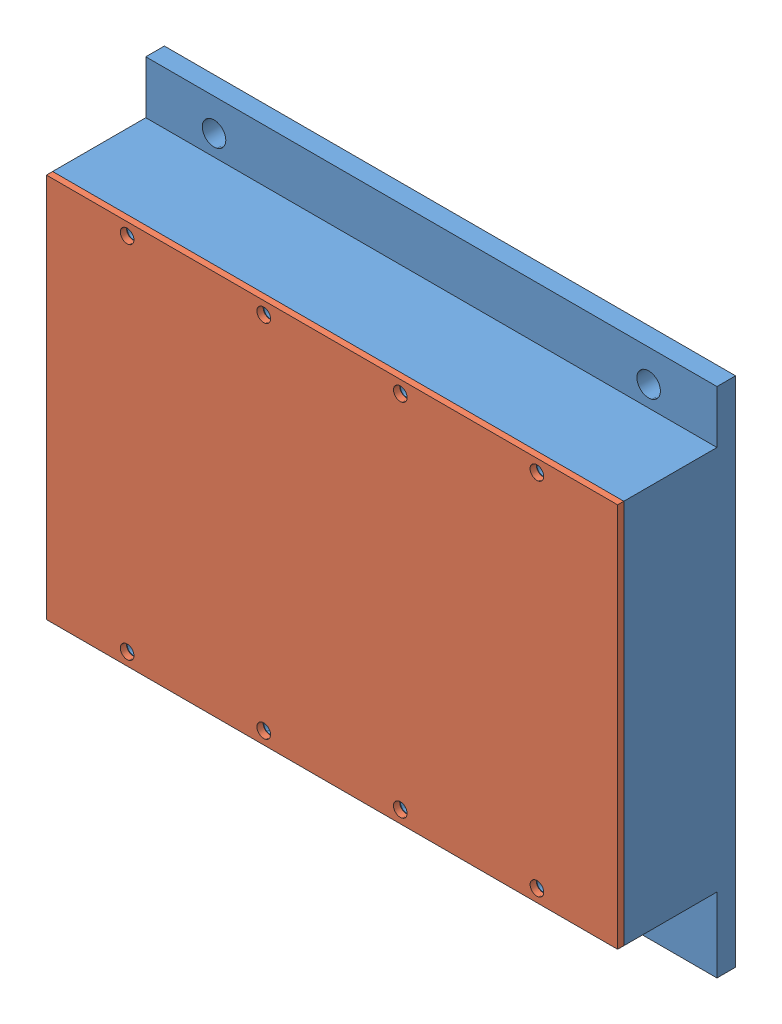
SolidWorks assembly B3_batterybox, configuration Default. Lengths in mm.
Overall size (92 82.5 20.29).
14 component instances, 6 part files, 40 mates.
Components (placement in the parent):
- B3_battery_case-1: B3_battery_case [Default] at (-27.6193 12.9444 0.2286) size (92 82.5 18)
- B3_battery_cover-1: B3_battery_cover [Default] at (-73.6193 43.9444 18.2286) size (92 62 1)
- B3_battery_insulator1-1: B3_battery_insulator1 [Default] at (-29.6748 38.9444 -2.4068) x (1 0 0) z (0 1 0) size (88.4 17 1)
- B3_battery_insulator1-2: B3_battery_insulator1 [Default] at (-25.5639 -14.0556 19.864) x (-1 0 0) z (0 1 0) size (88.4 17 1)
- B3_battery_insulator2-1: B3_battery_insulator2 [Default] at (15.5807 9.9046 1.8438) x (0 -1 0) z (0 0 1) size (52 1 17)
- B3_battery_insulator2-3: B3_battery_insulator2 [Default] at (-71.8193 9.9046 1.8438) x (0 -1 0) z (0 0 1) size (52 1 17)
- B3_battery_insulator3-1: B3_battery_insulator3 [Default] at (-40.702 30.9956 0.2286) x (1 0 0) z (0 -1 0) size (86.4 1 52)
- battery-8: battery [Default] at (-63.3443 -13.0556 8.4036) x (-0.702082 0 -0.712097) z (0.712097 0 -0.702082) size (14.35 52 14.35)
- battery-9: battery [Default] at (-48.9943 -13.0556 8.4036) x (-0.963236 0 -0.268658) z (0.268658 0 -0.963236) size (14.35 52 14.35)
- battery-10: battery [Default] at (-34.6443 -13.0556 8.4036) x (-0.96243 0 -0.271529) z (0.271529 0 -0.96243) size (14.35 52 14.35)
- battery-11: battery [Default] at (-20.2943 -13.0556 8.4036) x (0.998572 0 0.05343) z (-0.05343 0 0.998572) size (14.35 52 14.35)
- battery-12: battery [Default] at (-5.9443 -13.0556 8.4036) x (-0.654063 0 0.75644) z (-0.75644 0 -0.654063) size (14.35 52 14.35)
- battery-14: battery [Default] at (8.4057 -13.0556 8.4036) x (0.87582 0 0.482638) z (-0.482638 0 0.87582) size (14.35 52 14.35)
- B3_battery_insulator3-2: B3_battery_insulator3 [Default] at (-40.702 30.9956 15.5786) x (1 0 0) z (0 -1 0) size (86.4 1 52) (hidden)
Mates (geometry in assembly coordinates):
- Coincident13: coincident aligned: plane of B3_battery_insulator1-1 through (-71.8193 39.9444 17.2286) normal (0 0 1); plane of B3_battery_insulator1-2 through (16.5807 -13.0556 17.2286) normal (0 0 1)
- Coincident26: coincident anti-aligned: plane of B3_battery_insulator1-1 through (-29.6748 38.9444 -2.4068) normal (0 -1 0); plane of B3_battery_insulator2-1 through (16.5807 38.9444 0.2286) normal (0 1 0)
- Coincident29: coincident anti-aligned: plane of B3_battery_insulator1-1 through (-29.6748 38.9444 -2.4068) normal (0 -1 0); plane of B3_battery_insulator2-3 through (-70.8193 38.9444 0.2286) normal (0 1 0)
- Tangent30: tangent anti-aligned: plane of B3_battery_insulator2-1 through (15.5807 9.9046 1.8438) normal (-1 0 0); cylinder of battery-14 through (8.4057 37.9444 8.4036) axis (0 -1 0) radius 7.175
- Coincident46: coincident anti-aligned: plane of B3_battery_insulator1-2 through (-25.5639 -13.0556 19.864) normal (0 1 0); plane of battery-14 through (8.4057 -13.0556 8.4036) normal (0 -1 0)
- Coincident47: coincident anti-aligned: plane of B3_battery_insulator1-2 through (-25.5639 -13.0556 19.864) normal (0 1 0); plane of battery-12 through (-5.9443 -13.0556 8.4036) normal (0 -1 0)
- Tangent32: tangent anti-aligned: cylinder of battery-12 through (-5.9443 37.9444 8.4036) axis (0 -1 0) radius 7.175; cylinder of battery-14 through (8.4057 37.9444 8.4036) axis (0 -1 0) radius 7.175
- Coincident48: coincident anti-aligned: plane of B3_battery_insulator1-2 through (-25.5639 -13.0556 19.864) normal (0 1 0); plane of battery-11 through (-20.2943 -13.0556 8.4036) normal (0 -1 0)
- Tangent34: tangent anti-aligned: cylinder of battery-11 through (-20.2943 37.9444 8.4036) axis (0 -1 0) radius 7.175; cylinder of battery-12 through (-5.9443 37.9444 8.4036) axis (0 -1 0) radius 7.175
- Coincident49: coincident anti-aligned: plane of B3_battery_insulator1-2 through (-25.5639 -13.0556 19.864) normal (0 1 0); plane of battery-10 through (-34.6443 -13.0556 8.4036) normal (0 -1 0)
- Tangent36: tangent anti-aligned: cylinder of battery-10 through (-34.6443 37.9444 8.4036) axis (0 -1 0) radius 7.175; cylinder of battery-11 through (-20.2943 37.9444 8.4036) axis (0 -1 0) radius 7.175
- Coincident50: coincident anti-aligned: plane of B3_battery_insulator1-2 through (-25.5639 -13.0556 19.864) normal (0 1 0); plane of battery-9 through (-48.9943 -13.0556 8.4036) normal (0 -1 0)
- Tangent38: tangent anti-aligned: cylinder of battery-9 through (-48.9943 37.9444 8.4036) axis (0 -1 0) radius 7.175; cylinder of battery-10 through (-34.6443 37.9444 8.4036) axis (0 -1 0) radius 7.175
- Coincident51: coincident anti-aligned: plane of B3_battery_insulator1-2 through (-25.5639 -13.0556 19.864) normal (0 1 0); plane of battery-8 through (-63.3443 -13.0556 8.4036) normal (0 -1 0)
- Tangent40: tangent anti-aligned: cylinder of battery-8 through (-63.3443 37.9444 8.4036) axis (0 -1 0) radius 7.175; cylinder of battery-9 through (-48.9943 37.9444 8.4036) axis (0 -1 0) radius 7.175
- Coincident52: coincident anti-aligned: plane of B3_battery_insulator2-1 through (15.5807 9.9046 1.8438) normal (-1 0 0); plane of B3_battery_insulator3-2 through (15.5807 38.9444 16.5786) normal (1 0 0)
- Tangent44: tangent anti-aligned: cylinder of battery-10 through (-34.6443 37.9444 8.4036) axis (0 -1 0) radius 7.175; plane of B3_battery_insulator3-2 through (-40.702 30.9956 15.5786) normal (0 0 -1)
- Coincident53: coincident anti-aligned: plane of B3_battery_insulator1-1 through (-29.6748 38.9444 -2.4068) normal (0 -1 0); plane of B3_battery_insulator3-2 through (-70.8193 38.9444 16.5786) normal (0 1 0)
- 一致11: coincident anti-aligned: plane of B3_battery_case-1 through (-27.6193 12.9444 0.2286) normal (0 0 1); plane of B3_battery_insulator3-1 through (-40.702 30.9956 0.2286) normal (0 0 -1)
- 一致13: coincident anti-aligned: plane of B3_battery_insulator2-3 through (-70.8193 9.9046 1.8438) normal (1 0 0); plane of B3_battery_insulator3-1 through (-70.8193 38.9444 1.2286) normal (-1 0 0)
- 一致14: coincident aligned: plane of B3_battery_insulator2-3 through (-70.8193 -13.0556 0.2286) normal (0 -1 0); plane of B3_battery_insulator3-1 through (-70.8193 -13.0556 1.2286) normal (0 -1 0)
- 一致15: coincident anti-aligned: plane of B3_battery_insulator2-1 through (15.5807 9.9046 1.8438) normal (-1 0 0); plane of B3_battery_insulator3-1 through (15.5807 38.9444 1.2286) normal (1 0 0)
- 一致16: coincident aligned: plane of B3_battery_insulator2-1 through (16.5807 38.9444 0.2286) normal (0 0 -1); plane of B3_battery_insulator3-1 through (-40.702 30.9956 0.2286) normal (0 0 -1)
- 一致17: coincident aligned: plane of B3_battery_insulator1-1 through (-71.8193 39.9444 0.2286) normal (-1 0 0); plane of B3_battery_insulator2-3 through (-71.8193 9.9046 1.8438) normal (-1 0 0)
- 一致18: coincident anti-aligned: plane of B3_battery_insulator1-2 through (-25.5639 -13.0556 19.864) normal (0 1 0); plane of B3_battery_insulator2-3 through (-70.8193 -13.0556 0.2286) normal (0 -1 0)
- 一致19: coincident aligned: plane of B3_battery_insulator2-3 through (-70.8193 38.9444 0.2286) normal (0 0 -1); plane of B3_battery_insulator3-1 through (-40.702 30.9956 0.2286) normal (0 0 -1)
- 一致20: coincident aligned: plane of B3_battery_insulator1-2 through (-71.8193 -13.0556 17.2286) normal (-1 0 0); plane of B3_battery_insulator2-3 through (-71.8193 9.9046 1.8438) normal (-1 0 0)
- 一致21: coincident aligned: plane of B3_battery_insulator1-2 through (16.5807 -13.0556 17.2286) normal (0 0 1); plane of B3_battery_insulator2-3 through (-70.8193 38.9444 17.2286) normal (0 0 1)
- 正接1: tangent anti-aligned: plane of B3_battery_insulator3-1 through (-40.702 30.9956 1.2286) normal (0 0 1); cylinder of battery-14 through (8.4057 37.9444 8.4036) axis (0 -1 0) radius 7.175
- 正接4: tangent anti-aligned: plane of B3_battery_insulator3-1 through (-40.702 30.9956 1.2286) normal (0 0 1); cylinder of battery-12 through (-5.9443 37.9444 8.4036) axis (0 -1 0) radius 7.175
- 正接6: tangent anti-aligned: plane of B3_battery_insulator3-1 through (-40.702 30.9956 1.2286) normal (0 0 1); cylinder of battery-11 through (-20.2943 37.9444 8.4036) axis (0 -1 0) radius 7.175
- 正接7: tangent anti-aligned: plane of B3_battery_insulator3-1 through (-40.702 30.9956 1.2286) normal (0 0 1); cylinder of battery-10 through (-34.6443 37.9444 8.4036) axis (0 -1 0) radius 7.175
- 正接8: tangent anti-aligned: plane of B3_battery_insulator3-1 through (-40.702 30.9956 1.2286) normal (0 0 1); cylinder of battery-9 through (-48.9943 37.9444 8.4036) axis (0 -1 0) radius 7.175
- 正接9: tangent anti-aligned: plane of B3_battery_insulator3-1 through (-40.702 30.9956 1.2286) normal (0 0 1); cylinder of battery-8 through (-63.3443 37.9444 8.4036) axis (0 -1 0) radius 7.175
- 一致22: coincident anti-aligned: plane of B3_battery_case-1 through (-27.6193 12.9444 0.2286) normal (0 0 1); plane of B3_battery_insulator3-1 through (-40.702 30.9956 0.2286) normal (0 0 -1)
- 一致23: coincident anti-aligned: plane of B3_battery_case-1 through (-71.8193 39.9444 17.2286) normal (1 0 0); plane of B3_battery_insulator2-3 through (-71.8193 9.9046 1.8438) normal (-1 0 0)
- 一致24: coincident anti-aligned: plane of B3_battery_case-1 through (16.5807 -14.0556 17.2286) normal (0 1 0); plane of B3_battery_insulator1-2 through (-25.5639 -14.0556 19.864) normal (0 -1 0)
- 一致25: coincident anti-aligned: plane of B3_battery_case-1 through (-27.6193 12.9444 17.2286) normal (0 0 1); plane of B3_battery_cover-1 through (-73.6193 43.9444 17.2286) normal (0 0 -1)
- 一致26: coincident aligned: plane of B3_battery_case-1 through (-73.6193 43.9444 17.2286) normal (-1 0 0); plane of B3_battery_cover-1 through (-73.6193 43.9444 17.2286) normal (-1 0 0)
- 一致27: coincident aligned: plane of B3_battery_case-1 through (18.3807 43.9444 17.2286) normal (0 1 0); plane of B3_battery_cover-1 through (-73.6193 43.9444 17.2286) normal (0 1 0)
